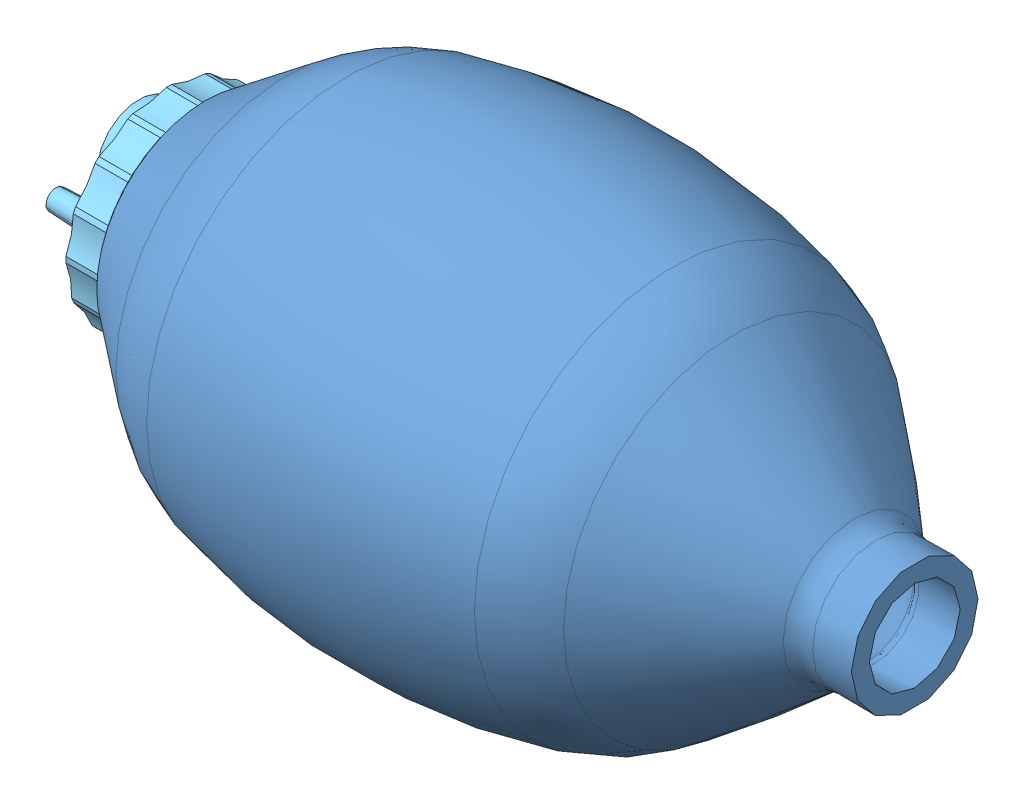
SolidWorks assembly Assy_Ambu-Bag, configuration Default. Lengths in mm.
Overall size (249.9 135.9 135.9).
6 component instances, 5 part files, 10 mates.
Components (placement in the parent):
- Ambu-Bag_Bellows-1: Ambu-Bag_Bellows [Default] at origin size (223 135.9 135.9)
- Assy_Ambu-Bag_Inlet_Inner-1: Assy_Ambu-Bag_Inlet_Inner [Default] at (-85.1284 0 0) x (-1 0 0) z (0 -0.924225 -0.381849) size (17.91 60.3 60.3)
  - Ambu-Bag_Inlet_Inner-1: Ambu-Bag_Inlet_Inner [Default] at origin size (17.56 60.3 60.3)
  - Ambu-Bag_Inlet_Inner_Seal-1: Ambu-Bag_Inlet_Inner_Seal [Default] at (2.65 0 0) x (0 0 -1) z (1 0 0) size (51 51 0.6)
  - Ambu-Bag_Inlet_Inner_Flange-1: Ambu-Bag_Inlet_Inner_Flange [Default] at (-0.35 0 0) size (9 26 26)
- Ambu-Bag_Inlet_Outer_Seal-1: Ambu-Bag_Inlet_Outer_Seal [Default] at (-93.2284 0 0) x (-1 0 0) z (0 -0.173648 0.984808) size (32.91 61.41 61.41)
Mates (geometry in assembly coordinates):
- Coincident1: coincident aligned: plane of Ambu-Bag_Bellows-1 through (-92.2284 0 -30.5199) normal (1 0 0); circle of Assy_Ambu-Bag_Inlet_Inner-1/Ambu-Bag_Inlet_Inner-1
- Concentric1: concentric anti-aligned: cylinder of Ambu-Bag_Bellows-1 through (0 0 0) axis (-1 0 0) radius 25.5; cylinder of Assy_Ambu-Bag_Inlet_Inner-1/Ambu-Bag_Inlet_Inner-1 through (-85.1284 0 0) axis (1 0 0) radius 24.35
- Coincident2: coincident anti-aligned: plane of Ambu-Bag_Bellows-1 through (-95.2284 0 -30.5199) normal (-1 0 0); plane of Ambu-Bag_Inlet_Outer_Seal-1 through (-95.2284 -27.5746 -4.8621) normal (1 0 0)
- Concentric2: concentric aligned: cylinder of Assy_Ambu-Bag_Inlet_Inner-1/Ambu-Bag_Inlet_Inner-1 through (-85.1284 0 0) axis (1 0 0) radius 24.35; cylinder of Ambu-Bag_Inlet_Outer_Seal-1 through (-93.2284 0 0) axis (1 0 0) radius 19.375
- Coincident3: coincident anti-aligned: plane of Ambu-Bag_Bellows-1 through (124.7716 0 -19.5) normal (1 0 0); plane of Assy_Ambu-Bag_Outlet-1/Ambu-Bag_Outlet-1 through (124.7716 19.8 0) normal (-1 0 0)
- Concentric3: concentric anti-aligned: cylinder of Ambu-Bag_Bellows-1 through (0 0 0) axis (-1 0 0) radius 14; cylinder of Assy_Ambu-Bag_Outlet-1/Ambu-Bag_Outlet-1 through (179.2716 0 0) axis (1 0 0) radius 13.4921
- Angle1: planar angle = 4.537856 rad aligned: plane of Ambu-Bag_Inlet_Outer_Seal-1 through (-93.2284 0 0) normal (0 -0.173648 0.984808)
- Distance1: distance = 1 mm anti-aligned: plane of Assy_PEEP_Valve-1/PEEP_Adapter_Outlet-1 through (179.2716 0 -28.8) normal (0 0 1); plane of Assy_Ambu-Bag_Outlet-1/Ambu-Bag_Outlet_Clip-1 through (174.8803 10.6286 -27.8) normal (0 0 -1)
- Concentric5: concentric anti-aligned: cylinder of Assy_Ambu-Bag_Outlet-1/Ambu-Bag_Outlet-1 through (149.2716 0 -15.3145) axis (0 0 -1) radius 8.4; cylinder of Assy_Pressure_Relief_Valve-1/Pressure Relief Valve Body-1 through (149.2716 0 29.4) axis (0 0 1) radius 11.2
- Distance2: distance = 4 mm anti-aligned: plane of Assy_Pressure_Relief_Valve-1/Pressure Relief Valve Body-1 through (160.4716 0 17.4) normal (0 0 -1); plane of Assy_Ambu-Bag_Outlet-1/Ambu-Bag_Outlet-1 through (158.7716 0 21.4) normal (0 0 1)
